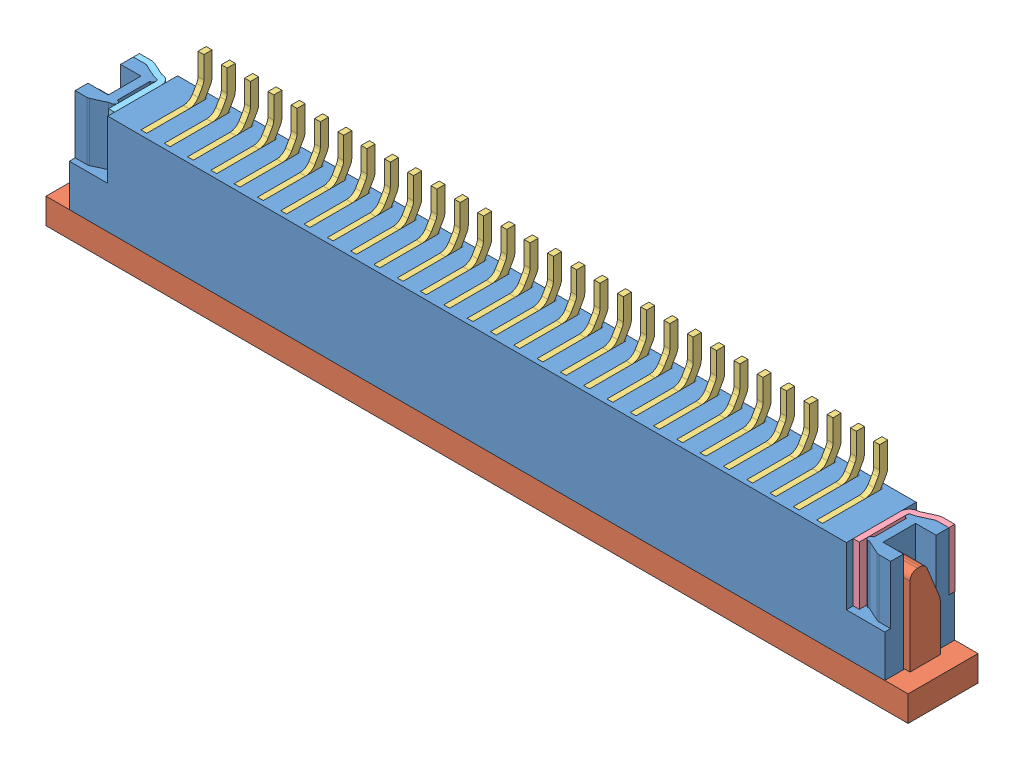
SolidWorks assembly 68613014422 (rev1), configuration Défaut. Lengths in mm.
Overall size (37 7.1 3.01).
34 component instances, 5 part files, 0 mates.
Components (placement in the parent):
- Gehõuse_7-1: Gehõuse_7 [Défaut] at origin size (35 5.4 3)
- Verschluss_7-1: Verschluss_7 [Défaut] at (0 -3.25 0) x (1 0 0) z (0 1 0) size (37 3 4.8)
- Pin1_7-1: Pin1_7 [Défaut] at (7.5 0 0) x (-1 0 0) z (0 0 1) size (0.25 6 2.8)
- Pin1_7-2: Pin1_7 [Défaut] at (6.5 0 0) x (-1 0 0) z (0 0 1) size (0.25 6 2.8)
- Pin1_7-3: Pin1_7 [Défaut] at (5.5 0 0) x (-1 0 0) z (0 0 1) size (0.25 6 2.8)
- Pin1_7-4: Pin1_7 [Défaut] at (4.5 0 0) x (-1 0 0) z (0 0 1) size (0.25 6 2.8)
- Pin1_7-5: Pin1_7 [Défaut] at (3.5 0 0) x (-1 0 0) z (0 0 1) size (0.25 6 2.8)
- Pin1_7-6: Pin1_7 [Défaut] at (2.5 0 0) x (-1 0 0) z (0 0 1) size (0.25 6 2.8)
- Pin1_7-7: Pin1_7 [Défaut] at (1.5 0 0) x (-1 0 0) z (0 0 1) size (0.25 6 2.8)
- Pin1_7-8: Pin1_7 [Défaut] at (0.5 0 0) x (-1 0 0) z (0 0 1) size (0.25 6 2.8)
- Pin1_7-9: Pin1_7 [Défaut] at (-1.5 0 0) x (-1 0 0) z (0 0 1) size (0.25 6 2.8)
- Pin1_7-10: Pin1_7 [Défaut] at (-2.5 0 0) x (-1 0 0) z (0 0 1) size (0.25 6 2.8)
- Pin1_7-11: Pin1_7 [Défaut] at (-3.5 0 0) x (-1 0 0) z (0 0 1) size (0.25 6 2.8)
- Pin1_7-12: Pin1_7 [Défaut] at (-4.5 0 0) x (-1 0 0) z (0 0 1) size (0.25 6 2.8)
- Pin1_7-13: Pin1_7 [Défaut] at (-5.5 0 0) x (-1 0 0) z (0 0 1) size (0.25 6 2.8)
- Pin1_7-14: Pin1_7 [Défaut] at (-6.5 0 0) x (-1 0 0) z (0 0 1) size (0.25 6 2.8)
- Pin1_7-15: Pin1_7 [Défaut] at (-7.5 0 0) x (-1 0 0) z (0 0 1) size (0.25 6 2.8)
- Pin1_7-16: Pin1_7 [Défaut] at (-0.5 0 0) x (-1 0 0) z (0 0 1) size (0.25 6 2.8)
- Pin1_7-17: Pin1_7 [Défaut] at (8.5 0 0) x (-1 0 0) z (0 0 1) size (0.25 6 2.8)
- Pin1_7-18: Pin1_7 [Défaut] at (9.5 0 0) x (-1 0 0) z (0 0 1) size (0.25 6 2.8)
- Pin1_7-19: Pin1_7 [Défaut] at (10.5 0 0) x (-1 0 0) z (0 0 1) size (0.25 6 2.8)
- Pin1_7-20: Pin1_7 [Défaut] at (11.5 0 0) x (-1 0 0) z (0 0 1) size (0.25 6 2.8)
- Pin1_7-21: Pin1_7 [Défaut] at (12.5 0 0) x (-1 0 0) z (0 0 1) size (0.25 6 2.8)
- Pin1_7-22: Pin1_7 [Défaut] at (13.5 0 0) x (-1 0 0) z (0 0 1) size (0.25 6 2.8)
- Pin1_7-23: Pin1_7 [Défaut] at (-8.5 0 0) x (-1 0 0) z (0 0 1) size (0.25 6 2.8)
- Pin1_7-24: Pin1_7 [Défaut] at (-9.5 0 0) x (-1 0 0) z (0 0 1) size (0.25 6 2.8)
- Pin1_7-25: Pin1_7 [Défaut] at (-10.5 0 0) x (-1 0 0) z (0 0 1) size (0.25 6 2.8)
- Pin1_7-26: Pin1_7 [Défaut] at (-11.5 0 0) x (-1 0 0) z (0 0 1) size (0.25 6 2.8)
- Pin1_7-27: Pin1_7 [Défaut] at (-12.5 0 0) x (-1 0 0) z (0 0 1) size (0.25 6 2.8)
- Pin1_7-28: Pin1_7 [Défaut] at (-13.5 0 0) x (-1 0 0) z (0 0 1) size (0.25 6 2.8)
- Pin1_7-29: Pin1_7 [Défaut] at (14.5 0 0) x (-1 0 0) z (0 0 1) size (0.25 6 2.8)
- Pin1_7-30: Pin1_7 [Défaut] at (-14.5 0 0) x (-1 0 0) z (0 0 1) size (0.25 6 2.8)
- Pin_rechts_7-1: Pin_rechts_7 [Défaut] at (15.98 0.9 0) x (-1 0 0) z (0 1 0) size (1.65 2.71 2.5)
- Pin_rechts_mir_6-1: Pin_rechts_mir_6 [Défaut] at (-15.98 0.9 0) x (1 0 0) z (0 1 0) size (1.65 2.71 2.5)
